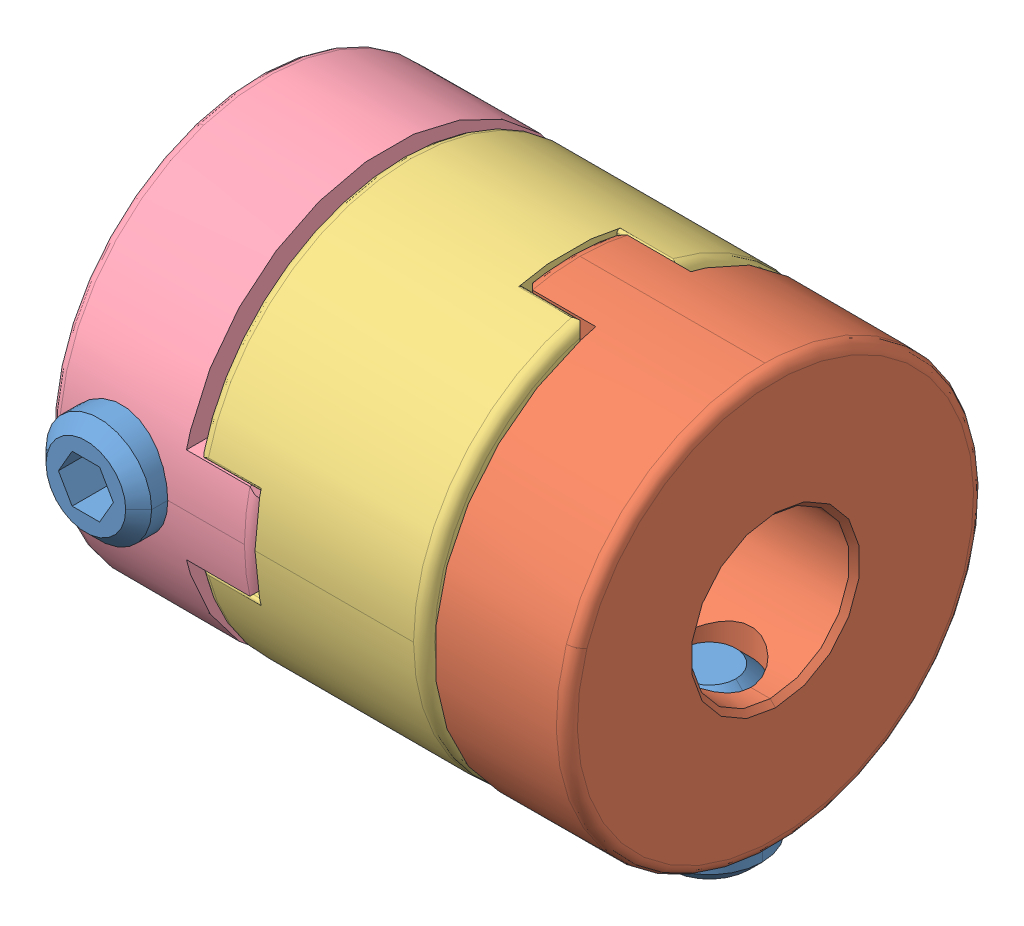
SolidWorks assembly CPO7_9_3_3, configuration Default. Lengths in mm.
Overall size (9.8 9.45 9.45).
5 component instances, 4 part files, 0 mates.
Components (placement in the parent):
- CPO7_9_3_3_3-1: CPO7_9_3_3_3 [Default] at (1.25 0 1.5) x (0 0 -1) z (-1 0 0) size (3 2 2)
- CPO7_9_3_3_3-2: CPO7_9_3_3_3 [Default] at (8.55 -1.5 0) x (0 1 0) z (1 0 0) size (3 2 2)
- CPO7_9_3_3_6-1: CPO7_9_3_3_6 [Default] at (9.8 0 0) x (-1 0 0) z (0 -1 0) size (3.9 9.45 9.45)
- CPO7_9_3_3_8-1: CPO7_9_3_3_8 [Default] at (4.8 0 0) size (4.4 7.9 7.9)
- CPO7_9_3_3_10-1: CPO7_9_3_3_10 [Default] at origin size (3.9 9.45 9.45)
